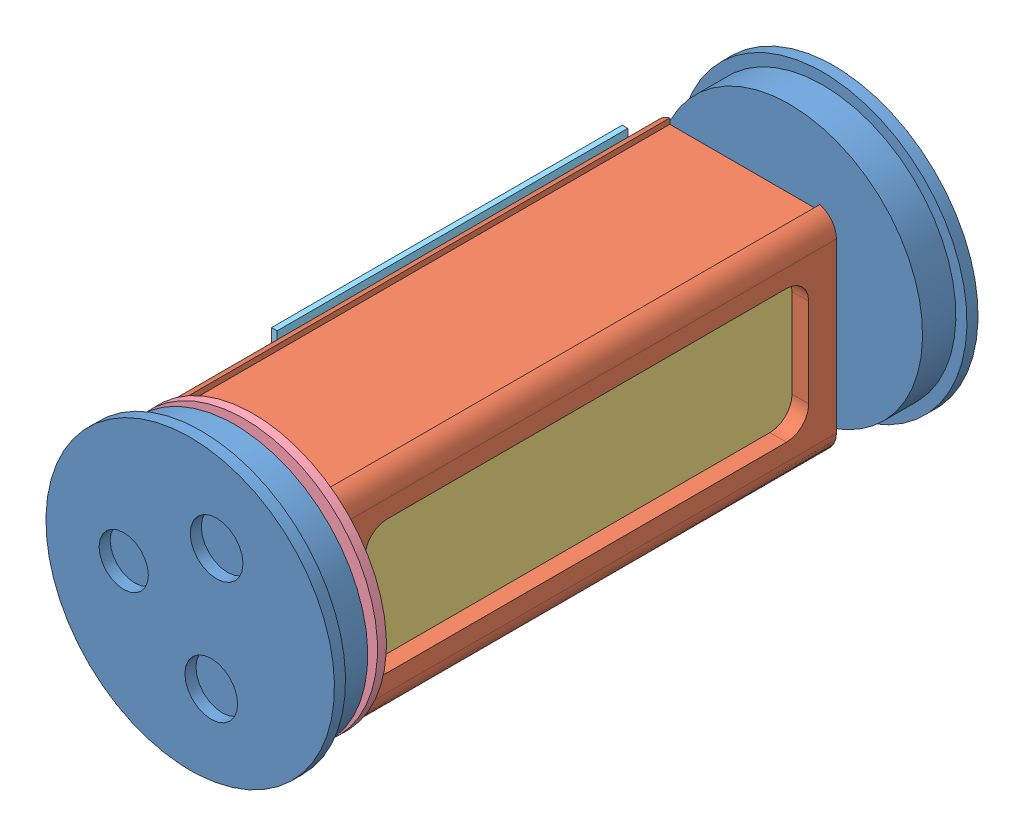
SolidWorks assembly Battery Pod, configuration Default. Lengths in mm.
Overall size (82.55 82.55 184.15).
8 component instances, 6 part files, 10 mates.
Components (placement in the parent):
- Battery Pod Tube-1: Battery Pod Tube [Default] at (30.9066 75.5653 -124.2248) size (82.55 82.55 177.8) (hidden)
- Battery Pod Front Lid-1: Battery Pod Front Lid [Default] at (30.9066 75.5653 53.5752) x (1 0 0) z (0 -1 0) size (82.55 12.7 82.55)
- Battery Holder-1: Battery Holder [Default] at (87.4904 45.3624 -37.9532) size (52.45 60.64 142.88)
  - Battery Holder-1: Battery Holder [Default] at (-82.8093 -0.1184 78.8907) size (52.45 60.64 142.88)
  - Battery-1: Battery [Default] at (-56.5838 1.4691 8.7232) x (0 0 -1) z (1 0 0) size (135.89 55.88 42.93)
- Battery Board-1: Battery Board [Default] at (30.9066 75.5653 38.715) size (76.2 76.2 2.54)
- Battery Pod Front Lid-2: Battery Pod Front Lid [Default] at (30.9066 75.5653 -124.2248) x (1 0 0) z (0 1 0) size (82.55 12.7 82.55)
- Battery Board 2-1: Battery Board 2 [Default] at (4.6811 75.3397 -44.511) x (0 0 -1) z (0 1 0) size (100.33 1.59 58.42)
Mates (geometry in assembly coordinates):
- Coincident1: coincident anti-aligned: plane of Battery Pod Tube-1 through (30.9066 75.5653 53.5752) normal (0 0 1); plane of Battery Pod Front Lid-1 through (30.9066 75.5653 53.5752) normal (0 0 -1)
- Concentric3: concentric anti-aligned: circle of Battery Pod Tube-1; circle of Battery Holder-1/Battery Holder-1
- Concentric4: concentric aligned: cylinder of Battery Pod Tube-1 through (30.9066 75.5653 53.5752) axis (0 0 -1) radius 38.1; cylinder of Battery Board-1 through (30.9066 75.5653 41.255) axis (0 0 -1) radius 38.1
- Coincident2: coincident anti-aligned: plane of Battery Holder-1/Battery-1 through (9.4436 102.7115 38.715) normal (0 0 1); plane of Battery Board-1 through (30.9066 75.5653 38.715) normal (0 0 -1)
- Coincident4: coincident anti-aligned: plane of Battery Pod Tube-1 through (30.9066 75.5653 53.5752) normal (0 0 1); plane of Battery Pod Front Lid-1 through (30.9066 75.5653 53.5752) normal (0 0 -1)
- Concentric6: concentric anti-aligned: cylinder of Battery Pod Tube-1 through (30.9066 75.5653 53.5752) axis (0 0 -1) radius 38.1; cylinder of Battery Pod Front Lid-1 through (30.9066 75.5653 44.0502) axis (0 0 1) radius 38.1
- Coincident5: coincident anti-aligned: plane of Battery Pod Tube-1 through (30.9066 75.5653 -124.2248) normal (0 0 -1); plane of Battery Pod Front Lid-2 through (30.9066 75.5653 -124.2248) normal (0 0 1)
- Concentric7: concentric aligned: cylinder of Battery Pod Tube-1 through (30.9066 75.5653 53.5752) axis (0 0 -1) radius 38.1; cylinder of Battery Pod Front Lid-2 through (30.9066 75.5653 -114.6998) axis (0 0 -1) radius 38.1
- Coincident6: coincident anti-aligned: plane of Battery Holder-1/Battery Holder-1 through (4.6811 46.8315 40.9375) normal (-1 0 0); plane of Battery Board 2-1 through (4.6811 104.5497 5.654) normal (1 0 0)
- Parallel1: parallel anti-aligned: line of Battery Holder-1/Battery Holder-1 through (4.6811 51.594 -101.9375) axis (0 0 1); line of Battery Board 2-1 through (3.0936 104.5497 5.654) axis (0 0 -1)
